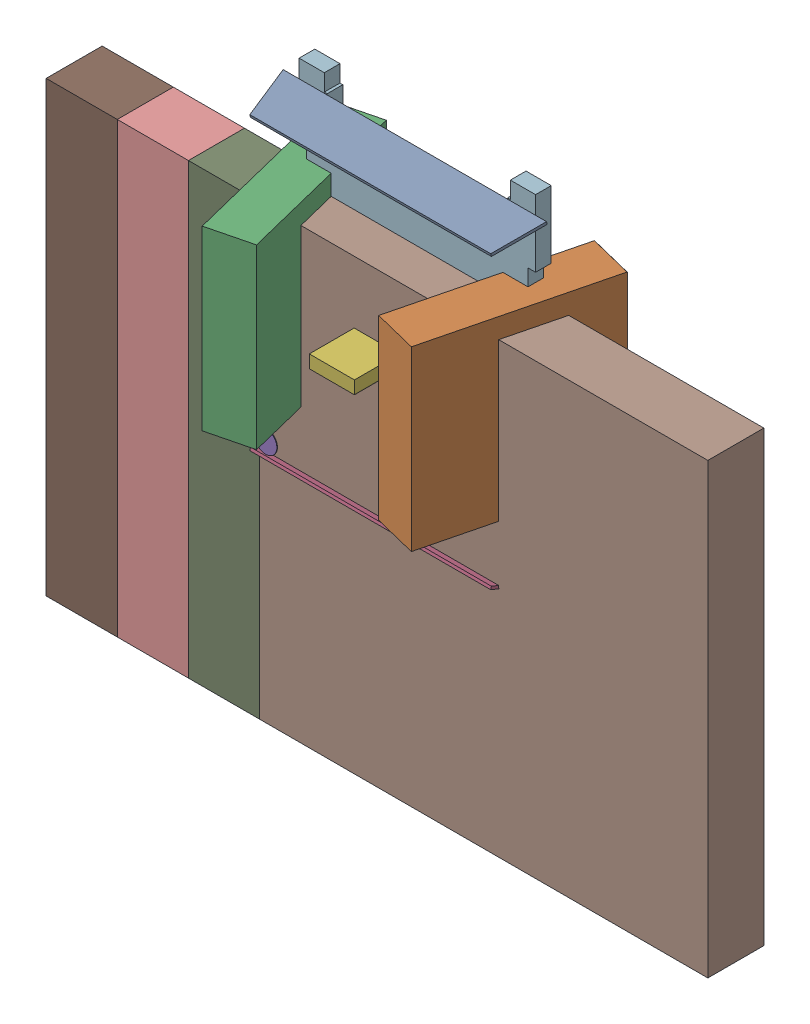
SolidWorks assembly Free-Models, configuration ﾃﾞﾌｫﾙﾄ. Lengths in mm.
Overall size (11.81 9.85 3.29).
24 component instances, 7 part files, 0 mates.
Components (placement in the parent):
- SIDE_S-1: SIDE_S [ﾃﾞﾌｫﾙﾄ] at (1.9 5.4223 0.705) x (1 0 0) z (0 0.970296 0.241922) size (4.7 0.82 0.05)
  - Extruded-1: Extruded [ﾃﾞﾌｫﾙﾄ] at origin size (4.7 0.82 0.05)
- SIDE_L-1: SIDE_L [ﾃﾞﾌｫﾙﾄ] at (4.1508 2.775 0.705) x (0.241922 0 -0.970296) z (-0.970296 0 -0.241922) size (3.19 3.17 0.81)
  - Extruded_2-1: Extruded_2 [ﾃﾞﾌｫﾙﾄ] at origin size (3.19 3.17 0.81)
- SIDE_L-1-1: SIDE_L-1 [ﾃﾞﾌｫﾙﾄ] at (-0.3508 2.775 0.705) x (-0.241922 0 -0.970296) z (0.970296 0 -0.241922) size (3.19 3.17 0.81)
  - Extruded_2-1: Extruded_2 [ﾃﾞﾌｫﾙﾄ] at origin size (3.19 3.17 0.81)
- SIDE_S-1-1: SIDE_S-1 [ﾃﾞﾌｫﾙﾄ] at (1.9 0.1277 0.705) x (-1 0 0) z (0 -0.970296 0.241922) size (4.7 0.82 0.05)
  - Extruded-1: Extruded [ﾃﾞﾌｫﾙﾄ] at origin size (4.7 0.82 0.05)
- 587257496-1: 587257496 [ﾃﾞﾌｫﾙﾄ] at (0.0484 0.4796 1.12) size (0.4 0.4 0.01)
  - Cylinder-1: Cylinder [ﾃﾞﾌｫﾙﾄ] at origin size (0.4 0.4 0.01)
- 750905040-1: 750905040 [ﾃﾞﾌｫﾙﾄ] at (1.9 2.775 1) size (0.8 0.23 0.8)
  - Extruded_3-1: Extruded_3 [ﾃﾞﾌｫﾙﾄ] at origin size (0.8 0.23 0.8)
- 266863104-1: 266863104 [ﾃﾞﾌｫﾙﾄ] at (1.9025 2.775 0.02) size (0.8 1.14 0.8)
  - Extruded_4-1: Extruded_4 [ﾃﾞﾌｫﾙﾄ] at origin size (0.8 1.14 0.8)
- 500156144-1: 500156144 [ﾃﾞﾌｫﾙﾄ] at (3.81 0 0) size (8 8 1)
  - Extruded_5-1: Extruded_5 [ﾃﾞﾌｫﾙﾄ] at origin size (8 8 1)
- 500156144-1-1: 500156144-1 [ﾃﾞﾌｫﾙﾄ] at (2.54 0 0) size (8 8 1)
  - Extruded_5-1: Extruded_5 [ﾃﾞﾌｫﾙﾄ] at origin size (8 8 1)
- 500156144-2-1: 500156144-2 [ﾃﾞﾌｫﾙﾄ] at (1.27 0 0) size (8 8 1)
  - Extruded_5-1: Extruded_5 [ﾃﾞﾌｫﾙﾄ] at origin size (8 8 1)
- 500156144-3-1: 500156144-3 [ﾃﾞﾌｫﾙﾄ] at origin size (8 8 1)
  - Extruded_5-1: Extruded_5 [ﾃﾞﾌｫﾙﾄ] at origin size (8 8 1)
- 500160368-1: 500160368 [ﾃﾞﾌｫﾙﾄ] at (1.905 3.335 0) size (5.15 5.03 0.28)
  - Extruded_6-1: Extruded_6 [ﾃﾞﾌｫﾙﾄ] at origin size (5.15 5.03 0.28)
